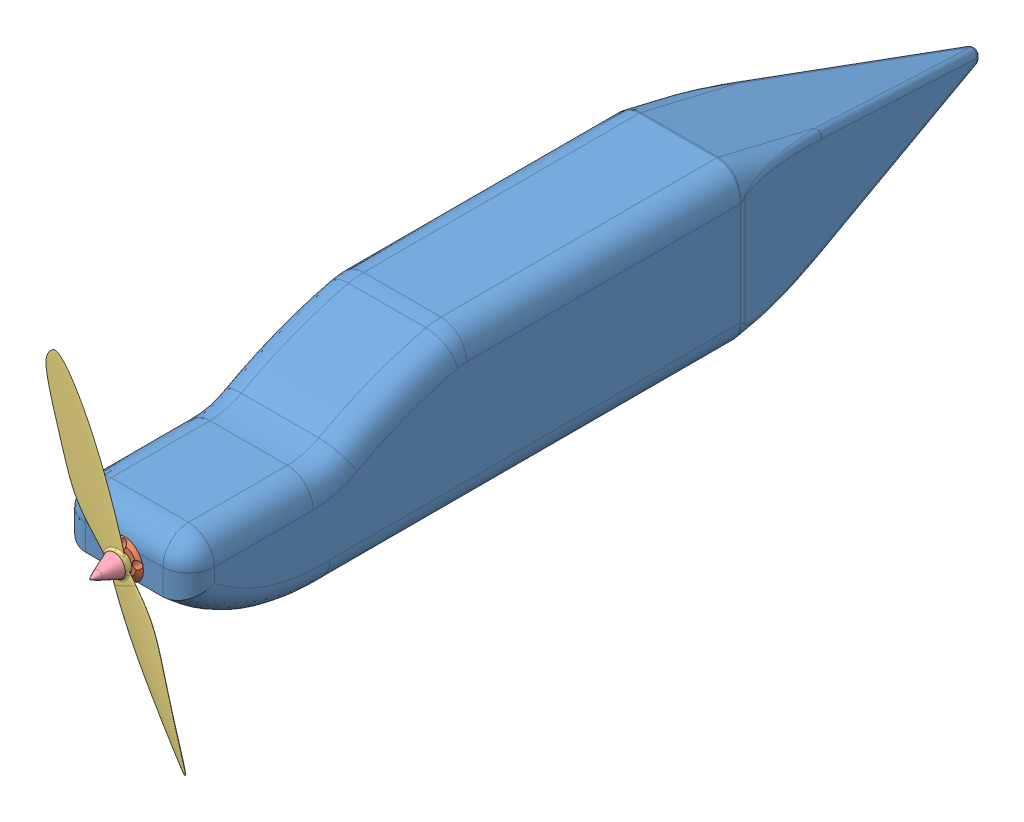
SolidWorks assembly Fuselage - propulsion system assembly, configuration Default. Lengths in mm.
Overall size (133.07 259.53 1086.93).
5 component instances, 4 part files, 2 mates.
Components (placement in the parent):
- Fuselage for propulsion system-1: Fuselage for propulsion system [Default] at (6.8192 -70.8224 152.6784) size (100 127.54 660.96)
- Propulsion system assembly-1: Propulsion system assembly [Default] at (-77.0564 -37.9716 340.8697) x (-0.121916 0.99254 0) z (0.99254 0.121916 0) size (257.04 52.9 102.49)
  - Electric motor-1: Electric motor [Default] at (12.8913 -4.1913 35.7137) size (40 40.5 40)
  - Propeller - 30deg twist-1: Propeller - 30deg twist [Default] at (9.5179 26.7661 36.8819) x (0.267188 0.098233 0.958624) z (-0.963211 -0.002607 0.268734) size (34.11 7.29 257.18)
  - Propeller spinner-1: Propeller spinner [Default] at (12.8913 24.3087 35.7137) size (17 24.4 17)
Mates (geometry in assembly coordinates):
- Concentric1: concentric anti-aligned: cylinder of Fuselage for propulsion system-1 through (-43.1808 -20.8224 342.6784) axis (0 0 1) radius 15; cylinder of Propulsion system assembly-1/Electric motor-1 through (-43.1808 -20.8224 336.6784) axis (0 0 -1) radius 15
- Coincident1: coincident anti-aligned: circle of Fuselage for propulsion system-1; circle of Propulsion system assembly-1/Electric motor-1
